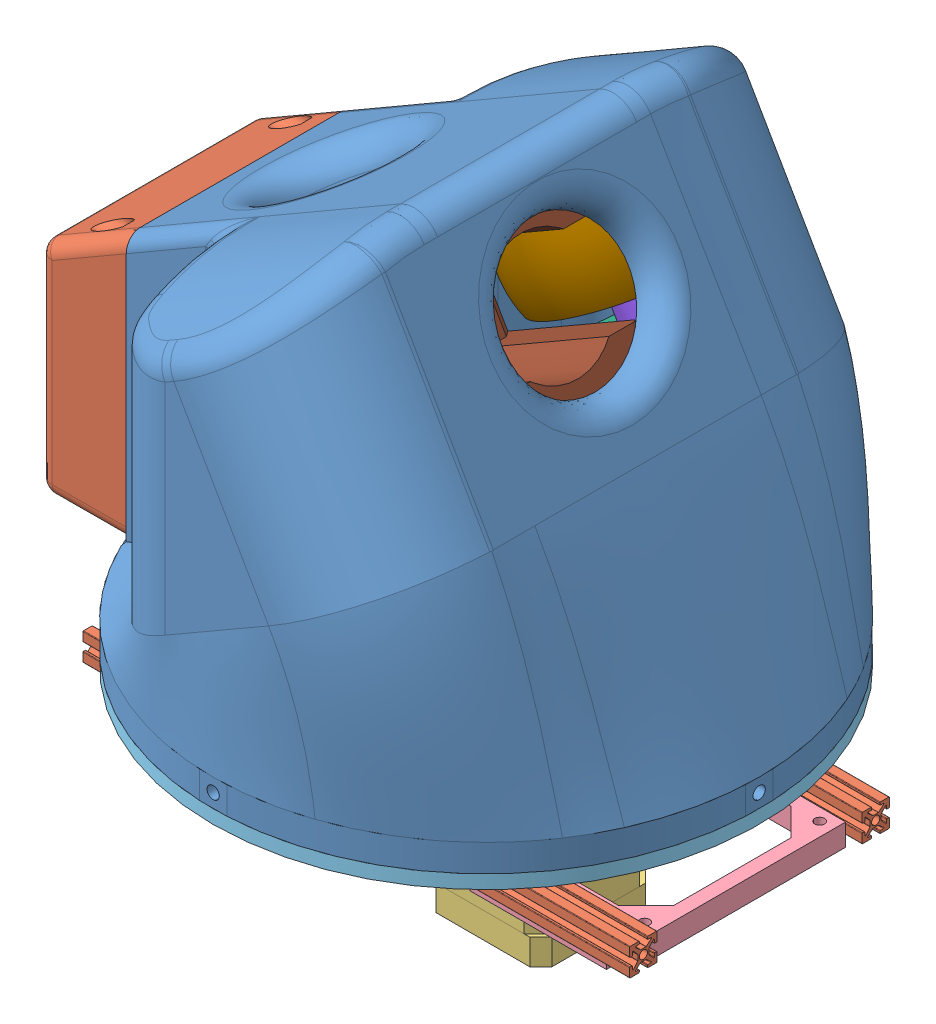
SolidWorks assembly Drivetrain, configuration Default. Lengths in mm.
Overall size (222.78 234.7 207.97).
33 component instances, 24 part files, 86 mates.
Components (placement in the parent):
- Swivel mockup-1: Swivel mockup [Default] at origin size (95 5 95)
- Swivel gear mount-1: Swivel gear mount [Default] at (0 15 0) x (1 0 0) z (0 0 -1) size (100 8 125) (hidden)
- Swivel mockup-2: Swivel mockup [Default] at (0 10 0) x (1 0 0) z (0 0 -1) size (95 5 95) (hidden)
- internal spur gear_am-1: internal spur gear_am [Metric - Internal spur gear 1M 60T 14.5PA 5FW ---S60S80mmOD 1AF] at (0 15 0) x (0 -1 0) z (-0.82495 0 -0.565205) size (5 80 80) (hidden)
- Makerbeam_200mm.stp-1: Makerbeam_200mm.stp [Default] at (100 -5 -42.5) x (0 0 1) z (-1 0 0) size (10 10 200)
- Makerbeam_200mm.stp-2: Makerbeam_200mm.stp [Default] at (-100 -5 42.5) x (0 0 -1) z (1 0 0) size (10 10 200)
- nema stepper mount-1: nema stepper mount [Default] at (20 -10 0) x (0 0 -1) z (1 0 0) size (92 8 40) (hidden)
- wire guard-1: wire guard [Default] at (-10 -10 0) x (0 0 1) z (-1 0 0) size (92 38 20.19) (hidden)
- Nema_17.ipt-1: Nema_17.ipt [Default] at (20 -41.6 0) x (1 0 0) z (0 0 -1) size (42.3 61.5 47.3)
- spur gear_am-1: spur gear_am [Metric - Spur gear 1M 20T 14.5PA 5FW ---S20N75H50L5N] at (20 15 0) x (0 -1 0) z (-0.912383 0 -0.409337) size (5 21.83 21.83) (hidden)
- vesc mount-2: vesc mount [Default] at (65 -10 0) x (0 0 1) z (-1 0 0) size (92 8 55)
- vesc mount-3: vesc mount [Default] at (-45 -10 0) x (0 0 -1) z (1 0 0) size (92 8 55)
- swivel base-1: swivel base [Default] at (0 15 0) x (-1 0 0) z (0 0 -1) size (200 15 200)
- dual bldc mount-1: dual bldc mount [Default] at (14.2798 92.9077 0) x (0 0 1) z (-0.866025 -0.5 0) size (166 110.38 63.18)
- Flipsky 6354 Mockup-1: Flipsky 6354 Mockup [Default] at (41.7798 45.2763 51.5) x (0.86599 0.499979 0.009091) z (-0.007873 -0.004545 0.999959) size (63 79 63)
- Flipsky 6354 Mockup-2: Flipsky 6354 Mockup [Default] at (41.7798 45.2763 -51.5) x (0.86599 0.499979 -0.009091) z (0.007873 0.004545 0.999959) size (63 79 63)
- motor shaft adapter-1: motor shaft adapter [Default] at (7.7798 104.166 -51.5) x (0.834097 0.481566 0.269029) z (-0.232986 -0.134514 0.963132) size (16 29 16)
- motor shaft adapter-2: motor shaft adapter [Default] at (7.7798 104.166 51.5) x (0.234871 0.135603 0.962521) z (-0.833568 -0.481261 0.271206) size (16 29 16)
- Wheel Mockup-1: Wheel Mockup [Default] at (-4.7202 125.8166 51.5) x (0.234871 0.135603 0.962521) z (-0.833568 -0.481261 0.271206) size (65 26 65)
- Wheel Mockup-2: Wheel Mockup [Default] at (-4.7202 125.8166 -51.5) x (0.834097 0.481566 0.269029) z (-0.232986 -0.134514 0.963132) size (65 26 65)
- 40mm Ping Pong Ball-1: 40mm Ping Pong Ball [Default] at (-34.204 107.8991 -0.7155) x (-0.128644 -0.857188 -0.498677) z (-0.94 0.265629 -0.214104) size (40 40 40)
- launcher guide-1: launcher guide [Default] at (-6.75 66.3324 0) x (0 0 1) z (-0.866025 -0.5 0) size (54 102 105)
- Rack Plunger-1: Rack Plunger [Default] at (-51.4121 97.7044 0) x (-0.866025 -0.5 0) z (0 0 -1) size (48 36 40)
- Assembly SERVO.stp-1: Assembly SERVO.stp [Default] at (-68.5901 101.2426 -7.3047) x (0.5 -0.866025 0) z (0 0 1) size (32.5 12.3 31.84)
  - Assembly servo inside.stp-1: Assembly servo inside.stp [Default] at (0 0 20.3449) size (26.5 12.3 31.84)
  - Assembly servo outside.stp-1: Assembly servo outside.stp [Default] at (0 0 20.3449) size (32.5 12.21 28.35)
- rack spur rectangular_am-1: rack spur rectangular_am [Metric - Rack-spur - rectangular 0.6M 20PA 5FW 2PH 43L---SAll] at (-94.2313 75.8694 2.5) x (0.866025 0.5 0) z (0 0 1) size (43 2.6 5)
- spur gear_am-2: spur gear_am [Metric - Spur gear 0.6M 40T 20PA 5FW ---S40N75H50L0.8N] at (-71.2776 105.8975 2.5) x (0 0 -1) z (-0.776478 -0.630144 0) size (5 25.15 25.15)
- Servo Holder Clip-1: Servo Holder Clip [Default] at (-73.5231 97.9867 19.4) x (-0.5 0.866025 0) z (0 0 1) size (40 4 11.2)
- IR Receiver Mockup-1: IR Receiver Mockup [Default] at (-48.9096 91.3549 -23) x (0.866025 0.5 0) z (0 0 1) size (20 8 10)
- IR Receiver Mockup-2: IR Receiver Mockup [Default] at (-31.5891 101.3549 23) x (-0.866025 -0.5 0) z (0 0 -1) size (20 8 10)
- Shell v3-1: Shell v3 [Default] at (0 20 0) x (-1 0 0) z (0 0 -1) size (200.63 163.7 207.97)
- Shell removable cover-2: Shell removable cover [Default] at (0 20 0) x (-1 0 0) z (0 0 -1) size (32 97.37 82.92)
Mates (geometry in assembly coordinates):
- Coincident2: coordinate: point of Swivel mockup-1
- Coincident3: coincident anti-aligned: plane of Swivel mockup-1 through (0 0 0) normal (0 -1 0); plane of Makerbeam_200mm.stp-2 through (-100 0 40.8) normal (0 1 0)
- Coincident4: coincident aligned: plane of Swivel mockup-1 through (0 5 47.5) normal (0 0 1); plane of Makerbeam_200mm.stp-2 through (-100 -3.3 47.5) normal (0 0 1)
- Coincident5: coincident anti-aligned: plane of Swivel mockup-1 through (0 0 0) normal (0 -1 0); plane of Makerbeam_200mm.stp-1 through (100 0 -47.3) normal (0 1 0)
- Coincident6: coincident aligned: plane of Swivel mockup-1 through (0 5 -47.5) normal (0 0 -1); plane of Makerbeam_200mm.stp-1 through (100 -3.3 -47.5) normal (0 0 -1)
- Coincident7: coincident aligned: plane of Makerbeam_200mm.stp-1 through (-100 -5 -42.5) normal (-1 0 0); plane of Makerbeam_200mm.stp-2 through (-100 -5 42.5) normal (-1 0 0)
- Distance1: distance = 100 mm anti-aligned: plane of Makerbeam_200mm.stp-1 through (-100 -5 -42.5) normal (-1 0 0)
- Concentric1: concentric anti-aligned: cylinder of Swivel mockup-1 through (0 5 0) axis (0 -1 0) radius 27; cylinder of Swivel mockup-2 through (0 5 0) axis (0 1 0) radius 27
- Coincident9: coincident anti-aligned: plane of Swivel mockup-1 through (0 5 0) normal (0 1 0); plane of Swivel mockup-2 through (0 5 0) normal (0 -1 0)
- Coincident11: coincident anti-aligned: plane of Makerbeam_200mm.stp-1 through (100 -10 -44.2) normal (0 -1 0); plane of wire guard-1 through (-10 -10 0) normal (0 1 0)
- Coincident13: coincident anti-aligned: plane of Swivel gear mount-1 through (0 10 0) normal (0 -1 0); plane of Swivel mockup-2 through (0 10 0) normal (0 1 0)
- Coincident14: coincident aligned: plane of Swivel gear mount-1 through (47.5 10 0) normal (1 0 0); plane of Swivel mockup-2 through (47.5 5 0) normal (1 0 0)
- Concentric3: concentric aligned: cylinder of Swivel gear mount-1 through (40.5 15 -40.5) axis (0 1 0) radius 2; cylinder of Swivel mockup-2 through (40.5 10 -40.5) axis (0 1 0) radius 2
- Concentric4: concentric aligned: cylinder of Swivel gear mount-1 through (-40.5 15 40.5) axis (0 1 0) radius 2; cylinder of Swivel mockup-2 through (-40.5 10 40.5) axis (0 1 0) radius 2
- Concentric7: concentric aligned: cylinder of Swivel mockup-1 through (0 5 0) axis (0 -1 0) radius 27; cylinder of wire guard-1 through (0 25 0) axis (0 -1 0) radius 17.5
- Parallel2: parallel aligned: plane of Makerbeam_200mm.stp-1 through (100 -9.8 -47.5) normal (0 0 -1); plane of wire guard-1 through (0 -13 -46) normal (0 0 -1)
- Concentric8: concentric aligned: cylinder of Swivel gear mount-1 through (0 10 0) axis (0 1 0) radius 40.1; cylinder of internal spur gear_am-1 through (0 25 0) axis (0 1 0) radius 40
- Coincident16: coincident aligned: plane of Swivel gear mount-1 through (0 15 0) normal (0 1 0); plane of internal spur gear_am-1 through (23.9236 15 16.3909) normal (0 1 0)
- Lock1: lock: unknown of Swivel gear mount-1; unknown of internal spur gear_am-1
- Coincident25: coincident anti-aligned: plane of Makerbeam_200mm.stp-2 through (-100 -10 37.7) normal (0 -1 0); plane of nema stepper mount-1 through (20 -10 0) normal (0 1 0)
- Coincident26: coincident aligned: plane of nema stepper mount-1 through (0 -13 46) normal (0 0 1); plane of wire guard-1 through (0 -13 46) normal (0 0 1)
- Coincident27: coincident anti-aligned: plane of nema stepper mount-1 through (0 -5 36.5) normal (-1 0 0); plane of wire guard-1 through (0 -5 -36.5) normal (1 0 0)
- Coincident28: coincident anti-aligned: plane of nema stepper mount-1 through (20 -13 0) normal (0 -1 0); plane of Nema_17.ipt-1 through (20 -13 0) normal (0 1 0)
- Concentric13: concentric anti-aligned: cylinder of nema stepper mount-1 through (20 -13 0) axis (0 1 0) radius 11; cylinder of Nema_17.ipt-1 through (20 -15 0) axis (0 -1 0) radius 2.5
- Parallel7: parallel aligned: plane of nema stepper mount-1 through (0 -13 46) normal (0 0 1); plane of Nema_17.ipt-1 through (2.85 -22.4 21.15) normal (0 0 1)
- Concentric14: concentric anti-aligned: cylinder of Nema_17.ipt-1 through (20 -15 0) axis (0 -1 0) radius 2.5; cylinder of spur gear_am-1 through (20 -35.0001 0) axis (0 1 0) radius 2.5
- Coincident31: coincident aligned: plane of internal spur gear_am-1 through (23.9236 15 16.3909) normal (0 1 0); plane of spur gear_am-1 through (20 15 0) normal (0 1 0)
- GearMate3: gear = 26.75 : 80 mm: circle of internal spur gear_am 3-1; circle of stepper spur gear-1
- Coincident32: coincident anti-aligned: plane of Makerbeam_200mm.stp-2 through (-100 -10 37.7) normal (0 -1 0); plane of vesc mount-2 through (65 -10 0) normal (0 1 0)
- Coincident33: coincident aligned: plane of nema stepper mount-1 through (0 -13 -46) normal (0 0 -1); plane of vesc mount-2 through (90 -13 -46) normal (0 0 -1)
- Coincident35: coincident anti-aligned: plane of nema stepper mount-1 through (40 -5 36.5) normal (1 0 0); plane of vesc mount-2 through (40 -5 -36.5) normal (-1 0 0)
- Coincident36: coincident anti-aligned: plane of wire guard-1 through (-20 -5 -36.5) normal (-1 0 0); plane of vesc mount-3 through (-20 -5 36.5) normal (1 0 0)
- Coincident38: coincident aligned: plane of wire guard-1 through (0 -13 46) normal (0 0 1); plane of vesc mount-3 through (-70 -13 46) normal (0 0 1)
- Coincident39: coincident anti-aligned: plane of Makerbeam_200mm.stp-2 through (-100 -10 44.2) normal (0 -1 0); plane of vesc mount-3 through (-45 -10 0) normal (0 1 0)
- Coincident40: coincident anti-aligned: plane of Swivel gear mount-1 through (0 15 0) normal (0 1 0); plane of swivel base-1 through (0 15 0) normal (0 -1 0)
- Concentric15: concentric aligned: cylinder of Swivel mockup-1 through (0 5 0) axis (0 -1 0) radius 27; cylinder of swivel base-1 through (0 20 0) axis (0 -1 0) radius 40
- Concentric16: concentric aligned: cylinder of Swivel gear mount-1 through (-40.5 15 -40.5) axis (0 1 0) radius 2; cylinder of swivel base-1 through (-40.5 20 -40.5) axis (0 1 0) radius 2
- Lock2: lock: unknown of Swivel gear mount-1; unknown of swivel base-1
- Coincident41: coincident anti-aligned: plane of swivel base-1 through (0 20 0) normal (0 1 0); plane of dual bldc mount-1 through (86.0247 20 -30) normal (0 -1 0)
- Concentric17: concentric anti-aligned: cylinder of swivel base-1 through (75 20 -20) axis (0 1 0) radius 2; cylinder of dual bldc mount-1 through (75 20 -20) axis (0 -1 0) radius 2.5
- Concentric19: concentric anti-aligned: cylinder of swivel base-1 through (75 20 20) axis (0 1 0) radius 2; cylinder of dual bldc mount-1 through (75 20 20) axis (0 -1 0) radius 2.5
- Coincident42: coincident anti-aligned: plane of dual bldc mount-1 through (14.2798 92.9077 0) normal (0.5 -0.866025 0); plane of Flipsky 6354 Mockup-1 through (14.2798 92.9077 51.5) normal (-0.5 0.866025 0)
- Concentric20: concentric aligned: cylinder of dual bldc mount-1 through (14.2798 92.9077 51.5) axis (0.5 -0.866025 0) radius 10; cylinder of Flipsky 6354 Mockup-1 through (14.2798 92.9077 51.5) axis (0.5 -0.866025 0) radius 5
- Tangent2: tangent anti-aligned: plane of dual bldc mount-1 through (7.3745 100.4679 0) normal (0.866025 0.5 0); cylinder of Flipsky 6354 Mockup-1 through (14.1066 92.8077 73.4991) axis (-0.5 0.866025 0) radius 2
- Coincident43: coincident anti-aligned: plane of dual bldc mount-1 through (14.2798 92.9077 0) normal (0.5 -0.866025 0); plane of Flipsky 6354 Mockup-2 through (14.2798 92.9077 -51.5) normal (-0.5 0.866025 0)
- Concentric21: concentric aligned: cylinder of dual bldc mount-1 through (14.2798 92.9077 -51.5) axis (0.5 -0.866025 0) radius 10; cylinder of Flipsky 6354 Mockup-2 through (14.2798 92.9077 -51.5) axis (0.5 -0.866025 0) radius 5
- Tangent3: tangent anti-aligned: plane of dual bldc mount-1 through (7.3745 100.4679 0) normal (0.866025 0.5 0); cylinder of Flipsky 6354 Mockup-2 through (14.1066 92.8077 -73.4991) axis (-0.5 0.866025 0) radius 2
- Concentric22: concentric aligned: cylinder of Flipsky 6354 Mockup-2 through (14.2798 92.9077 -51.5) axis (0.5 -0.866025 0) radius 5; cylinder of motor shaft adapter-1 through (7.7798 104.166 -51.5) axis (0.5 -0.866025 0) radius 8
- Concentric23: concentric aligned: cylinder of Flipsky 6354 Mockup-1 through (14.2798 92.9077 51.5) axis (0.5 -0.866025 0) radius 5; cylinder of motor shaft adapter-2 through (7.7798 104.166 51.5) axis (0.5 -0.866025 0) radius 8
- Distance3: distance = 3 mm anti-aligned: plane of motor shaft adapter-2 through (7.7798 104.166 51.5) normal (0.5 -0.866025 0); plane of dual bldc mount-1 through (9.2798 101.5679 0) normal (-0.5 0.866025 0)
- Distance4: distance = 3 mm anti-aligned: plane of motor shaft adapter-1 through (7.7798 104.166 -51.5) normal (0.5 -0.866025 0); plane of dual bldc mount-1 through (9.2798 101.5679 0) normal (-0.5 0.866025 0)
- Concentric24: concentric aligned: cylinder of motor shaft adapter-2 through (7.7798 104.166 51.5) axis (0.5 -0.866025 0) radius 8; cylinder of Wheel Mockup-1 through (-11.2202 137.075 51.5) axis (0.5 -0.866025 0) radius 2
- Concentric25: concentric aligned: cylinder of motor shaft adapter-1 through (7.7798 104.166 -51.5) axis (0.5 -0.866025 0) radius 8; cylinder of Wheel Mockup-2 through (-11.2202 137.075 -51.5) axis (0.5 -0.866025 0) radius 2
- Coincident44: coincident anti-aligned: plane of motor shaft adapter-1 through (-8.2117 128.4196 -58.2107) normal (-0.605856 -0.349791 -0.714552); plane of Wheel Mockup-2 through (-12.499 125.9444 -53.3639) normal (0.605856 0.349791 0.714552)
- Coincident45: coincident anti-aligned: plane of motor shaft adapter-1 through (-6.7202 129.2807 -51.5) normal (-0.5 0.866025 0); plane of Wheel Mockup-2 through (-6.7202 129.2807 -51.5) normal (0.5 -0.866025 0)
- Coincident46: coincident anti-aligned: plane of motor shaft adapter-2 through (-5.093 130.2202 58.1685) normal (0.620188 0.358066 0.697965); plane of Wheel Mockup-1 through (-0.9052 132.6381 53.207) normal (-0.620188 -0.358066 -0.697965)
- Coincident47: coincident anti-aligned: plane of motor shaft adapter-2 through (-6.7202 129.2807 51.5) normal (-0.5 0.866025 0); plane of Wheel Mockup-1 through (-6.7202 129.2807 51.5) normal (0.5 -0.866025 0)
- Coincident48: coincident anti-aligned: plane of dual bldc mount-1 through (-18 85.8179 0) normal (-0.866025 -0.5 0); plane of launcher guide-1 through (-6.75 66.3324 0) normal (0.866025 0.5 0)
- Slot1: slot aligned: plane of launcher guide-1 through (-6.75 66.3324 -12.8) normal (0 0 -1); cylinder of dual bldc mount-1 through (-10.1708 72.2574 -15) axis (-0.866025 -0.5 0) radius 2.5; cylinder of launcher guide-1 through (-11.375 74.3431 -15) axis (-0.866025 -0.5 0) radius 2.2
- Slot2: slot aligned: plane of launcher guide-1 through (-6.75 66.3324 17.2) normal (0 0 -1); cylinder of dual bldc mount-1 through (-10.1708 72.2574 15) axis (-0.866025 -0.5 0) radius 2.5; cylinder of launcher guide-1 through (-11.375 74.3431 15) axis (-0.866025 -0.5 0) radius 2.2
- Coincident49: coincident anti-aligned: plane of dual bldc mount-1 through (9.2798 101.5679 0) normal (-0.5 0.866025 0); plane of launcher guide-1 through (-74.2917 53.3179 0) normal (0.5 -0.866025 0)
- Tangent5: tangent aligned: sphere of 40mm Ping Pong Ball-1; cylinder of launcher guide-1 through (-35.8301 106.7006 0) axis (0.866025 0.5 0) radius 20.75
- Concentric26: concentric aligned: cylinder of launcher guide-1 through (-35.8301 106.7006 0) axis (0.866025 0.5 0) radius 20.75; cylinder of Rack Plunger-1 through (-55.7422 95.2044 0) axis (0.866025 0.5 0) radius 20
- Coincident51: coincident anti-aligned: plane of launcher guide-1 through (-46.9808 76.0141 -25) normal (-0.866025 -0.5 0); plane of Assembly SERVO.stp-1/Assembly servo outside.stp-1 through (-68.9949 114.1436 28.8402) normal (0.866025 0.5 0)
- Concentric27: concentric anti-aligned: cylinder of launcher guide-1 through (-59.9914 102.5491 -8.4853) axis (-0.866025 -0.5 0) radius 3.25; cylinder of Rack Plunger-1 through (-95.4919 82.0528 -8.4853) axis (0.866025 0.5 0) radius 2.5
- Parallel9: parallel aligned: plane of launcher guide-1 through (-11.0801 63.8324 25) normal (0 0 1); plane of Assembly SERVO.stp-1/Assembly servo outside.stp-1 through (-68.5901 101.2426 28.8402) normal (0 0 1)
- Coincident56: coincident anti-aligned: plane of Rack Plunger-1 through (-55.7422 95.2044 0) normal (-0.866025 -0.5 0); plane of rack spur rectangular_am-1 through (-56.9922 97.3694 -2.5) normal (0.866025 0.5 0)
- Coincident57: coincident anti-aligned: plane of Rack Plunger-1 through (-94.2313 75.8694 -2.5) normal (-0.5 0.866025 0); plane of rack spur rectangular_am-1 through (-94.2313 75.8694 -2.5) normal (0.5 -0.866025 0)
- Coincident60: coincident aligned: plane of Rack Plunger-1 through (-91.7313 71.5393 2.5) normal (0 0 1); plane of rack spur rectangular_am-1 through (-95.5313 78.1211 2.5) normal (0 0 1)
- LimitDistance1: limit distance = 0.0075 mm anti-aligned: plane of launcher guide-1 through (-30.9987 52.3324 0) normal (0.866025 0.5 0); plane of Rack Plunger-1 through (-55.7422 95.2044 0) normal (-0.866025 -0.5 0)
- Concentric28: concentric anti-aligned: cylinder of Assembly SERVO.stp-1/Assembly servo inside.stp-1 through (-71.2776 105.8975 1.0402) axis (0 0 -1) radius 2.1; cylinder of spur gear_am-2 through (-71.2776 105.8975 -47.5001) axis (0 0 1) radius 0.4
- Coincident61: coincident aligned: plane of rack spur rectangular_am-1 through (-95.5313 78.1211 2.5) normal (0 0 1); plane of spur gear_am-2 through (-71.2776 105.8975 2.5) normal (0 0 1)
- Tangent7: tangent anti-aligned: unknown of 40mm Ping Pong Ball-1; plane of Rack Plunger-1 through (-51.4121 97.7044 0) normal (0.866025 0.5 0)
- Coincident67: coincident anti-aligned: plane of launcher guide-1 through (-43.1231 45.3324 0) normal (-0.866025 -0.5 0); plane of Servo Holder Clip-1 through (-73.5231 97.9867 19.4) normal (0.866025 0.5 0)
- Concentric34: concentric anti-aligned: cylinder of launcher guide-1 through (-66.0231 84.9963 19.4) axis (-0.866025 -0.5 0) radius 2.25; cylinder of Servo Holder Clip-1 through (-69.4872 82.9963 19.4) axis (0.866025 0.5 0) radius 2.5
- Concentric35: concentric anti-aligned: cylinder of launcher guide-1 through (-81.0231 110.9771 19.4) axis (-0.866025 -0.5 0) radius 2.25; cylinder of Servo Holder Clip-1 through (-84.4872 108.9771 19.4) axis (0.866025 0.5 0) radius 2.5
- Coincident68: coincident anti-aligned: plane of launcher guide-1 through (-6.75 66.3324 23) normal (0 0 1); plane of IR Receiver Mockup-2 through (-35.5891 108.2831 23) normal (0 0 -1)
- Coincident69: coincident anti-aligned: plane of launcher guide-1 through (-28.125 103.3549 25) normal (-0.5 0.866025 0); plane of IR Receiver Mockup-2 through (-31.5891 101.3549 23) normal (0.5 -0.866025 0)
- Coincident70: coincident anti-aligned: plane of launcher guide-1 through (-27.5346 54.3324 25) normal (0.866025 0.5 0); plane of IR Receiver Mockup-2 through (-52.9096 98.2831 23) normal (-0.866025 -0.5 0)
- Coincident71: coincident anti-aligned: plane of launcher guide-1 through (-6.75 66.3324 -23) normal (0 0 -1); plane of IR Receiver Mockup-1 through (-52.9096 98.2831 -23) normal (0 0 1)
- Coincident73: coincident anti-aligned: plane of launcher guide-1 through (-28.125 103.3549 -25) normal (-0.5 0.866025 0); plane of IR Receiver Mockup-1 through (-48.9096 91.3549 -23) normal (0.5 -0.866025 0)
- Coincident74: coincident anti-aligned: plane of launcher guide-1 through (-27.5346 54.3324 -25) normal (0.866025 0.5 0); plane of IR Receiver Mockup-1 through (-52.9096 98.2831 -23) normal (-0.866025 -0.5 0)
- Coincident77: coincident aligned: circle of swivel base-1; circle of Shell v3-1
- Coincident88: coincident anti-aligned: plane of Shell v3-1 through (0 20 0) normal (0 0 -1)
- Coincident89: coincident anti-aligned: plane of swivel base-1 through (0 15 0) normal (0 0 -1)
- Coincident94: coordinate: point of Shell v3-1; point of Shell removable cover-2
